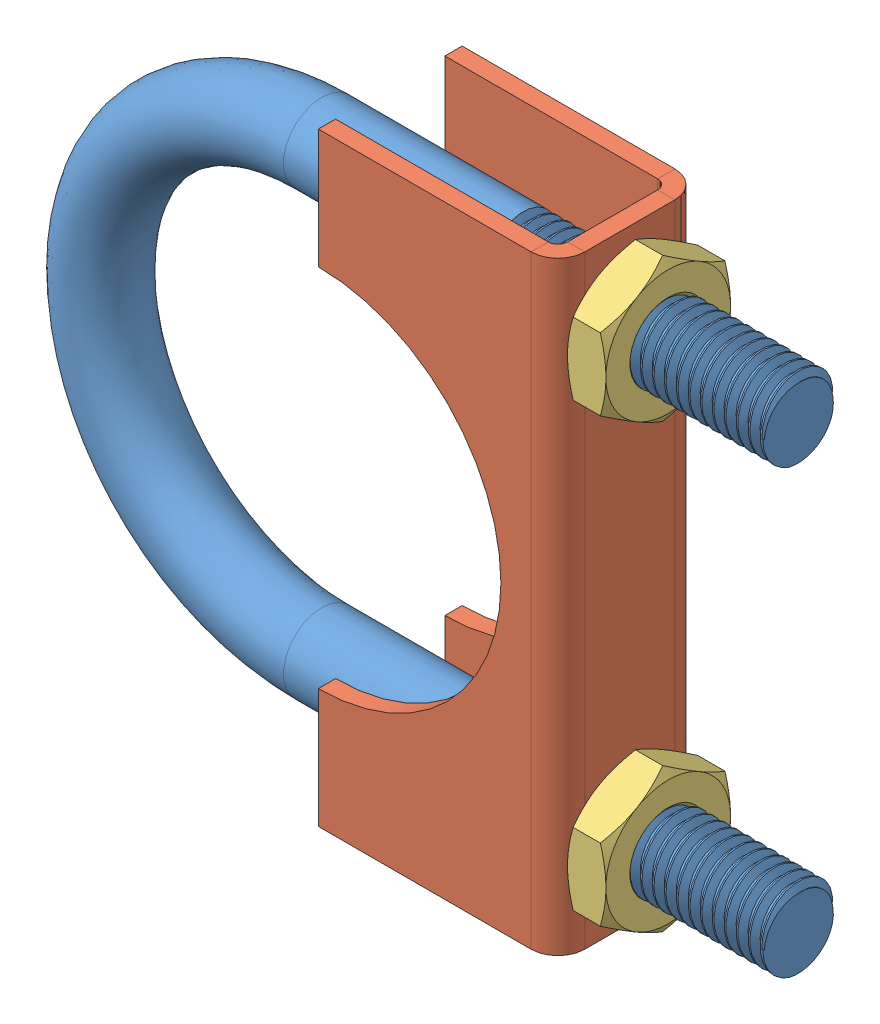
SolidWorks assembly Grampo_Montagem, configuration Valor predeterminado. Lengths in mm.
Overall size (77.62 63 15).
4 component instances, 3 part files, 6 mates.
Components (placement in the parent):
- Abracadeira_Grampo_U_1.5_-1: Abracadeira_Grampo_U_1.5_ [Valor predeterminado] at (10.6131 2.2934 307.0451) size (77.62 54.23 8.06)
- Abracadeira_Grampo_U_1.5_Suporte-2: Abracadeira_Grampo_U_1.5_Suporte [Valor predeterminado] at (17.7529 33.7934 314.5451) x (0 0 -1) z (0 -1 0) size (15 25 63)
- hex nut jam_am-2: hex nut jam_am [B18.2.4.5M - Hex jam nut,  M8 x 1.25 --D-N] at (46.7529 -20.7566 307.0451) x (0 0 -1) z (1 0 0) size (13 15.01 4)
- hex nut jam_am-3: hex nut jam_am [B18.2.4.5M - Hex jam nut,  M8 x 1.25 --D-N] at (46.7529 25.3434 307.0451) x (0 0 -1) z (1 0 0) size (13 15.01 4)
Mates (geometry in assembly coordinates):
- Concêntrico5: concentric anti-aligned: cylinder of Abracadeira_Grampo_U_1.5_-1 through (60.6131 25.3434 307.0451) axis (-1 0 0) radius 4; cylinder of Abracadeira_Grampo_U_1.5_Suporte-2 through (17.7519 25.3434 307.0451) axis (1 0 0) radius 4.5
- Concêntrico8: concentric aligned: cylinder of Abracadeira_Grampo_U_1.5_-1 through (10.6131 -20.7566 307.0451) axis (1 0 0) radius 4; cylinder of Abracadeira_Grampo_U_1.5_Suporte-2 through (17.7519 -20.7566 307.0451) axis (1 0 0) radius 4.5
- Concêntrico15: concentric: cylinder of Abracadeira_Grampo_U_1.5_Suporte-2 through (17.7519 -20.7566 307.0451) axis (1 0 0) radius 4.5; cylinder of hex nut jam_am-2 through (21.7154 -20.7566 307.0451) axis (1 0 0) radius 4
- Coincidente7: coincident: plane of Abracadeira_Grampo_U_1.5_Suporte-2 through (42.7529 -29.2066 314.5451) normal (1 0 0); plane of hex nut jam_am-2 through (42.7529 -13.251 307.0451) normal (-1 0 0)
- Concêntrico16: concentric aligned: cylinder of Abracadeira_Grampo_U_1.5_Suporte-2 through (17.7519 25.3434 307.0451) axis (1 0 0) radius 4.5; cylinder of hex nut jam_am-3 through (21.7154 25.3434 307.0451) axis (1 0 0) radius 4
- Coincidente8: coincident anti-aligned: plane of Abracadeira_Grampo_U_1.5_Suporte-2 through (42.7529 -29.2066 314.5451) normal (1 0 0); plane of hex nut jam_am-3 through (42.7529 32.849 307.0451) normal (-1 0 0)
